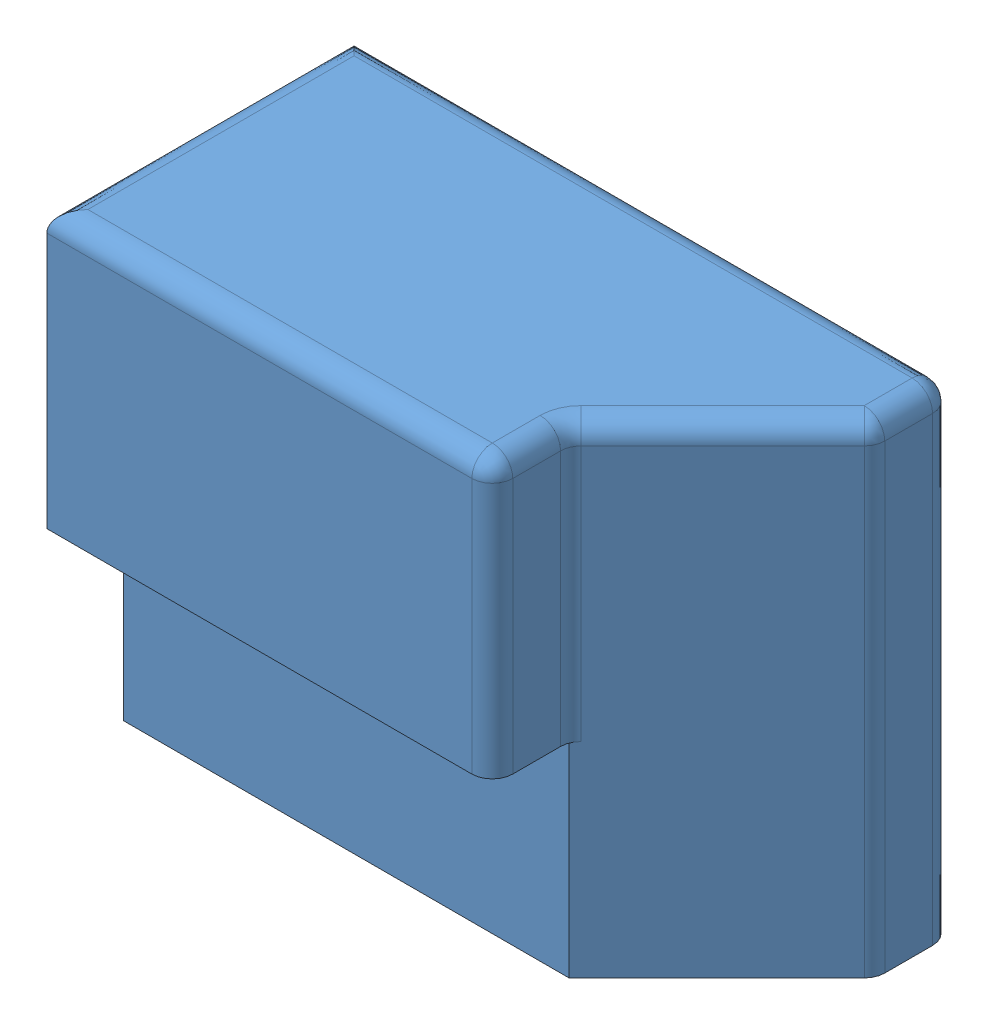
SolidWorks assembly NEW IDEA FOR ACTUATOR, configuration Default. Lengths in mm.
Overall size (14.86 11.94 7.62).
2 component instances, 2 part files, 3 mates.
Components (placement in the parent):
- NEW ACTUATOR-1: NEW ACTUATOR [Default] at (-0.2331 -0.4625 -11.3485) size (14.86 11.94 7.62)
- NEW DESIGN BLACK PIECE-1: NEW DESIGN BLACK PIECE [Default] at (3.5769 3.3475 -11.0945) x (0 -1 0) z (0 0 1) size (5.08 8.76 2.54)
Mates (geometry in assembly coordinates):
- Coincident1: coincident anti-aligned: plane of NEW ACTUATOR-1 through (8.0219 7.7925 -8.5545) normal (0 0 -1); plane of NEW DESIGN BLACK PIECE-1 through (3.5769 3.3475 -8.5545) normal (0 0 1)
- LimitAngle1: limit planar angle = 1.570796 rad aligned: plane of NEW DESIGN BLACK PIECE-1 through (3.5769 5.8875 -8.5545) normal (0 1 0); plane of NEW ACTUATOR-1 through (-0.2331 -0.4625 -3.7285) normal (-1 0 0)
- Concentric4: concentric aligned: cylinder of NEW ACTUATOR-1 through (3.5769 3.3475 -6.6495) axis (0 0 -1) radius 0.635; cylinder of NEW DESIGN BLACK PIECE-1 through (3.5769 3.3475 -8.5545) axis (0 0 -1) radius 1.016
